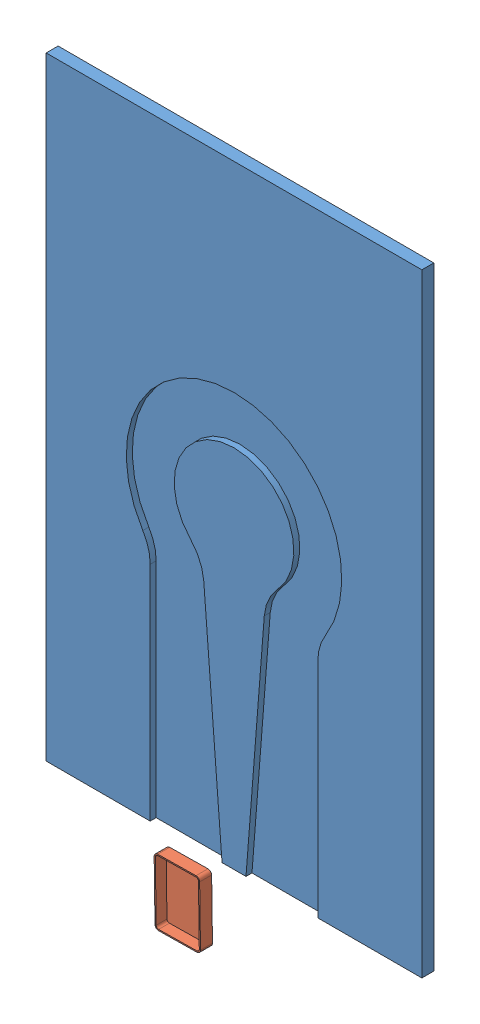
SolidWorks assembly Assemblage1, configuration Défaut. Lengths in mm.
Overall size (313.72 602.81 15).
2 component instances, 2 part files, 3 mates.
Components (placement in the parent):
- Pièce1 fer a cheval Oxsyy-1: Pièce1 fer a cheval Oxsyy [Défaut] at (13.262 50.6185 5) size (313.72 602.81 10)
- boite Oxsyy-1: boite Oxsyy [Défaut] at (-29.0777 -247.4752 0) x (-0.999901 -0.014091 0) z (0 0 1) size (38 55 10)
Mates (geometry in assembly coordinates):
- Parallèle1: parallel anti-aligned: plane of Pièce1 fer a cheval Oxsyy-1 through (13.262 50.6185 0) normal (0 0 1); plane of boite Oxsyy-1 through (-13.4245 -222.7522 0) normal (0 0 -1)
- Contrainte de trajectoire2: path: moEndPointRef_w of boite Oxsyy-1; curve of Pièce1 fer a cheval Oxsyy-1
- Coïncidente8: coincident: curve of Pièce1 fer a cheval Oxsyy-1; moEndPointRef_w of boite Oxsyy-1
